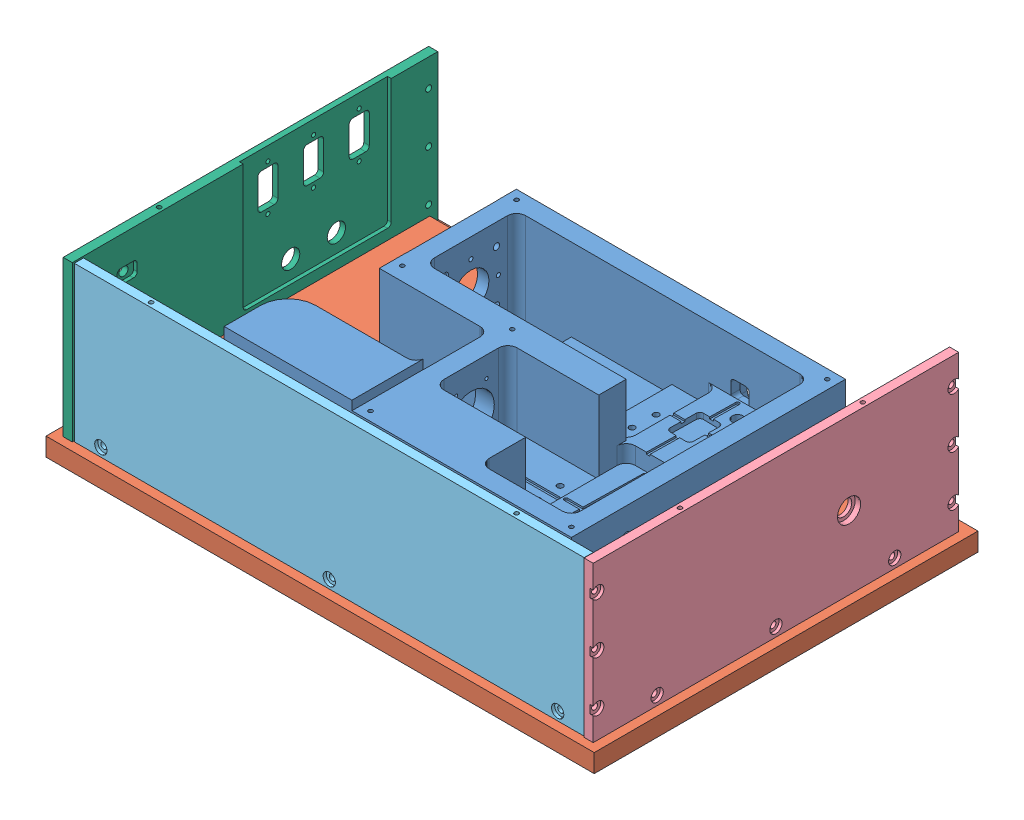
SolidWorks assembly FCLassemv2, configuration Default. Lengths in mm.
Overall size (300 95 210).
6 component instances, 6 part files, 9 mates.
Components (placement in the parent):
- laser_cavity2-1: laser_cavity2 [Default] at origin size (190 60 150)
- outer_base-1: outer_base [Default] at (103.7137 -20.7 18.9109) x (-1 0 0) z (0 0 -1) size (300 19.28 210)
- TEC-1: TEC [Default] at (83.9148 -2.42 -42.5275) size (50 3.42 50)
- outer_wall_front-1: outer_wall_front [Default] at (271.5781 -84.0632 25.1448) x (0 -1 0) z (-1 0 0) size (85 200 5)
- outer_wall_sides-1: outer_wall_sides [Default] at (118.0743 -4.0928 111.4234) size (279 85 5)
- outer_wall_electronics-1: outer_wall_electronics [Default] at (-18.4219 -84.0632 8.866) x (0 -1 0) z (1 0 0) size (85 200 5)
Mates (geometry in assembly coordinates):
- Concentric2: concentric aligned: circle of laser_cavity2-1; circle of outer_base-1
- Concentric3: concentric anti-aligned: circle of laser_cavity2-1; circle of outer_base-1
- Coincident1: coincident anti-aligned: plane of outer_base-1 through (103.7137 -2.42 18.9109) normal (0 1 0); plane of TEC-1 through (83.9148 -2.42 -42.5275) normal (0 -1 0)
- Coincident2: coincident anti-aligned: plane of laser_cavity2-1 through (0 1 0) normal (0 -1 0); plane of TEC-1 through (83.9148 1 -42.5275) normal (0 1 0)
- Coincident4: coincident anti-aligned: plane of outer_base-1 through (266.5781 -1.42 111.4234) normal (1 0 0); plane of outer_wall_front-1 through (266.5781 -84.0632 25.1448) normal (-1 0 0)
- Concentric6: concentric aligned: circle of outer_base-1; circle of outer_wall_sides-1
- Coincident5: coincident anti-aligned: plane of outer_base-1 through (-13.4219 -1.42 111.4234) normal (-1 0 0); plane of outer_wall_electronics-1 through (-13.4219 -84.0632 8.866) normal (1 0 0)
- Coincident6: coincident anti-aligned: plane of outer_base-1 through (103.7137 -10.7 18.9109) normal (0 1 0); plane of outer_wall_electronics-1 through (-13.4219 -10.7 -82.9754) normal (0 -1 0)
- Coincident7: coincident anti-aligned: plane of outer_base-1 through (103.7137 -10.7 18.9109) normal (0 1 0); plane of outer_wall_front-1 through (266.5781 -10.7 116.9863) normal (0 -1 0)
